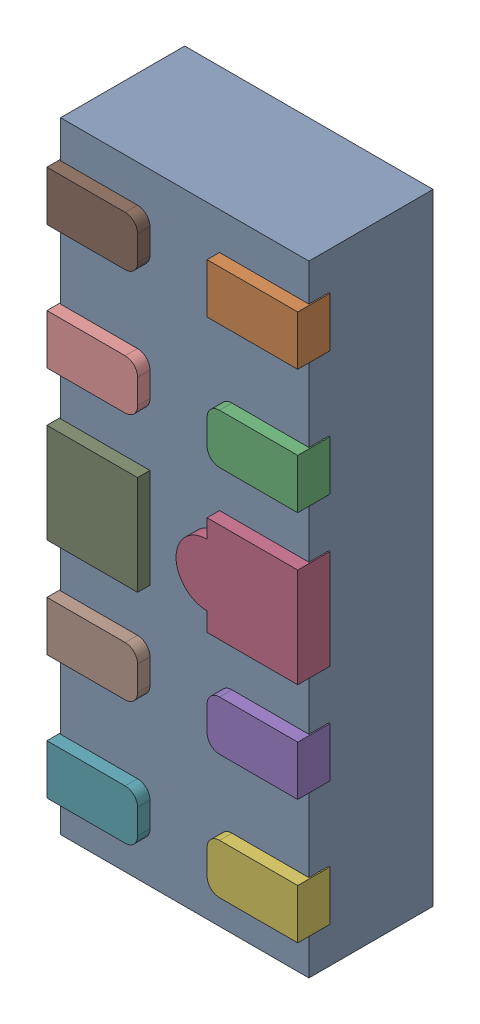
SolidWorks assembly D38, configuration Défaut. Lengths in mm.
Overall size (1.01 2.5 0.55).
12 component instances, 5 part files, 0 mates.
Components (placement in the parent):
- UDFN10-1: UDFN10 [Défaut] at (73.6831 -12.739 -1.1719) x (0 -1 0) z (1 0 0) size (2.5 0.55 1.01)
  - User Library-UDFN10_Body-1: User Library-UDFN10_Body [Défaut] at (1.0785 0.9721 1.8983) size (2.5 0.5 1)
  - User Library-UDFN10_Pin1-1: User Library-UDFN10_Pin1 [Défaut] at (0.0785 1.0521 2.2208) x (0 0 -1) z (-1 0 0) size (0.37 0.13 0.2)
  - User Library-UDFN10_Pin2-1: User Library-UDFN10_Pin2 [Défaut] at (0.5785 1.0521 2.2208) x (0 0 1) z (1 0 0) size (0.37 0.13 0.2)
  - User Library-UDFN10_Pin4-1: User Library-UDFN10_Pin4 [Défaut] at (1.0785 0.9221 2.2208) x (0 0 1) z (-1 0 0) size (0.49 0.13 0.4)
  - User Library-UDFN10_Pin2-2: User Library-UDFN10_Pin2 [Défaut] at (1.5785 0.9221 2.2208) x (0 0 1) z (-1 0 0) size (0.37 0.13 0.2)
  - User Library-UDFN10_Pin2-3: User Library-UDFN10_Pin2 [Défaut] at (2.0785 0.9221 2.2208) x (0 0 1) z (-1 0 0) size (0.37 0.13 0.2)
  - User Library-UDFN10_Pin2-4: User Library-UDFN10_Pin2 [Défaut] at (2.0785 0.9221 1.5758) x (0 0 -1) z (1 0 0) size (0.37 0.13 0.2)
  - User Library-UDFN10_Pin2-5: User Library-UDFN10_Pin2 [Défaut] at (1.5785 0.9221 1.5758) x (0 0 -1) z (1 0 0) size (0.37 0.13 0.2)
  - User Library-UDFN10_Pin3-1: User Library-UDFN10_Pin3 [Défaut] at (1.0785 0.9221 1.5758) x (0 0 1) z (-1 0 0) size (0.37 0.13 0.4)
  - User Library-UDFN10_Pin2-6: User Library-UDFN10_Pin2 [Défaut] at (0.5785 0.9221 1.5758) x (0 0 -1) z (1 0 0) size (0.37 0.13 0.2)
  - User Library-UDFN10_Pin2-7: User Library-UDFN10_Pin2 [Défaut] at (0.0785 0.9221 1.5758) x (0 0 -1) z (1 0 0) size (0.37 0.13 0.2)
